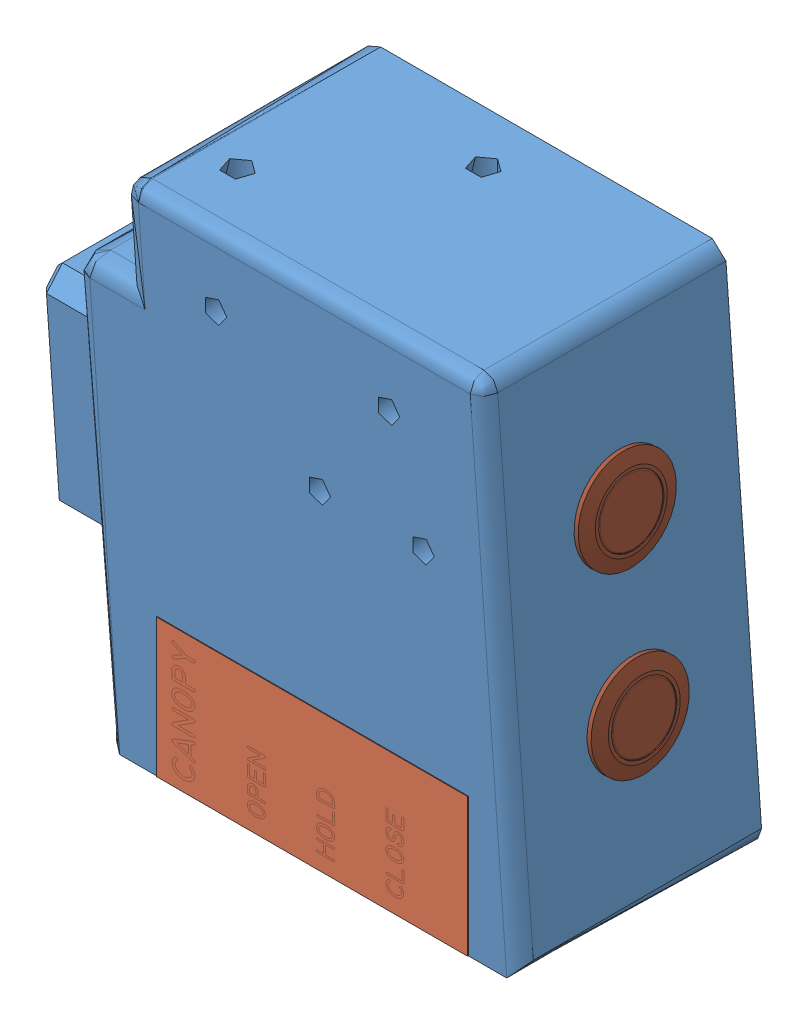
SolidWorks assembly Canopy Control, configuration Default. Lengths in mm.
Overall size (95.05 109.82 44.58).
14 component instances, 11 part files, 9 mates.
Components (placement in the parent):
- Canopy Bracket-1: Canopy Bracket [Default] at origin size (94.96 92.07 44.45)
- Canopy Placard-1: Canopy Placard [Default] at origin size (57.15 25.4 0.13)
- 100SPxT8B13M1QEH - SWITCH, TOGGLE, SPDT, 18mm BAT-1: 100SPxT8B13M1QEH - SWITCH, TOGGLE, SPDT, 18mm BAT [100SP4T8B13M1QEH] at (-3235.1372 6192.9038 -21.1023) x (-1 0 0) z (0 -1 0) size (19 18.28 42.41)
  - 100-300SPXBODY-1: 100-300SPXBODY [Default] at origin size (12.7 6.86 8.38)
  - 100SPXBRACKET_1-1: 100SPXBRACKET_1 [100SP4T8B13M1QEH] at (0 0 0.19) size (12.7 6.86 8.7)
  - 100T8-1: 100T8 [Default] at (0 0 13.35) x (-0.976296 0 -0.21644) z (-0.21644 0 0.976296) size (7.5 7.5 28.63)
  - 100B13BUSHING-1: 100B13BUSHING [Default] at (0 0 0.51) x (-1 0 0) z (0 0 1) size (12.18 12.24 11.89)
  - 100-300SPXM1-1: 100-300SPXM1 [Default] x (-1 0 0) z (0 0 -1) size (12.56 4.43 3.96)
  - HDW17 - LOCKING RING, B13-1: HDW17 - LOCKING RING, B13 [Default] at (0 0 13.3378) x (0 1 0) z (1 0 0) size (18.24 3.3 19)
  - HDW12 - LOCK WASHER, B13-1: HDW12 - LOCK WASHER, B13 [Default] at (0 0 12.779) x (1 0 0) z (0 -1 0) size (15.06 0.56 15.06)
  - HDW4 - NUT, B13-1: HDW4 - NUT, B13 [Default] at (0 0 10.7978) x (0.996778 -0.080205 0) z (-0.080205 -0.996778 0) size (14 1.98 16.16)
  - HDW4 - NUT, B13-2: HDW4 - NUT, B13 [Default] at (0 0 17.5288) x (0.98588 -0.167452 0) z (-0.167452 -0.98588 0) size (14 1.98 16.16)
- PV2F24011 - SWITCH, PUSHBUTTON, FLAT, OFF-(ON)-1: PV2F24011 - SWITCH, PUSHBUTTON, FLAT, OFF-(ON) [Default] at (-3213.703 6201.6991 -23.495) x (0.074829 -0.997196 0) z (0 0 1) size (18 18.5 18)
- PV2F24011 - SWITCH, PUSHBUTTON, FLAT, OFF-(ON)-2: PV2F24011 - SWITCH, PUSHBUTTON, FLAT, OFF-(ON) [Default] at (-3216.0788 6233.3601 -23.495) x (0.074829 -0.997196 0) z (0 0 1) size (18 18.5 18)
Mates (geometry in assembly coordinates):
- Concentric63: concentric aligned: cylinder of Canopy Bracket-1 through (-3235.1372 6175.375 -21.1023) axis (0 -1 0) radius 6.35; cylinder of 100SPxT8B13M1QEH - SWITCH, TOGGLE, SPDT, 18mm BAT-1/100B13BUSHING-1 through (-3235.1372 6183.5038 -21.1023) axis (0 -1 0) radius 5.925
- Parallel22: parallel anti-aligned: plane of Canopy Bracket-1 through (0 0 -4.7625) normal (0 0 -1); plane of 100SPxT8B13M1QEH - SWITCH, TOGGLE, SPDT, 18mm BAT-1/100SPXBRACKET_1-1 through (-3235.1372 6184.7738 -17.6723) normal (0 0 1)
- Coincident181: coincident anti-aligned: plane of Canopy Bracket-1 through (0 6175.375 0) normal (0 -1 0); plane of 100SPxT8B13M1QEH - SWITCH, TOGGLE, SPDT, 18mm BAT-1/HDW4 - NUT, B13-2 through (-3235.1372 6175.375 -21.1023) normal (0 1 0)
- Concentric65: concentric aligned: cylinder of Canopy Bracket-1 through (-3206.4858 6202.2407 -23.495) axis (-0.997196 -0.074829 0) radius 8; cylinder of PV2F24011 - SWITCH, PUSHBUTTON, FLAT, OFF-(ON)-1 through (-3202.1081 6202.5692 -23.495) axis (-0.997196 -0.074829 0) radius 7.9
- Coincident183: coincident anti-aligned: plane of Canopy Bracket-1 through (-3206.3649 6264.275 -44.45) normal (0.997196 0.074829 0); plane of PV2F24011 - SWITCH, PUSHBUTTON, FLAT, OFF-(ON)-1 through (-3202.4775 6212.4693 -13.595) normal (-0.997196 -0.074829 0)
- Parallel26: parallel aligned: plane of Canopy Bracket-1 through (0 0 -4.7625) normal (0 0 -1); plane of PV2F24011 - SWITCH, PUSHBUTTON, FLAT, OFF-(ON)-1 through (-3215.4655 6200.4638 -27.995) normal (0 0 -1)
- Concentric66: concentric: cylinder of Canopy Bracket-1 through (-3208.8616 6233.9017 -23.495) axis (-0.997196 -0.074829 0) radius 8; cylinder of PV2F24011 - SWITCH, PUSHBUTTON, FLAT, OFF-(ON)-2 through (-3202.5627 6203.3514 -23.495) axis (-0.997196 -0.074829 0) radius 7.9
- Coincident184: coincident: plane of Canopy Bracket-1 through (-3206.3649 6264.275 -44.45) normal (0.997196 0.074829 0); plane of PV2F24011 - SWITCH, PUSHBUTTON, FLAT, OFF-(ON)-2 through (-3202.9321 6213.2515 -13.595) normal (-0.997196 -0.074829 0)
- Parallel27: parallel aligned: plane of PV2F24011 - SWITCH, PUSHBUTTON, FLAT, OFF-(ON)-1 through (-3215.4655 6200.4638 -27.995) normal (0 0 -1); plane of PV2F24011 - SWITCH, PUSHBUTTON, FLAT, OFF-(ON)-2 through (-3217.8413 6232.1248 -27.995) normal (0 0 -1)
